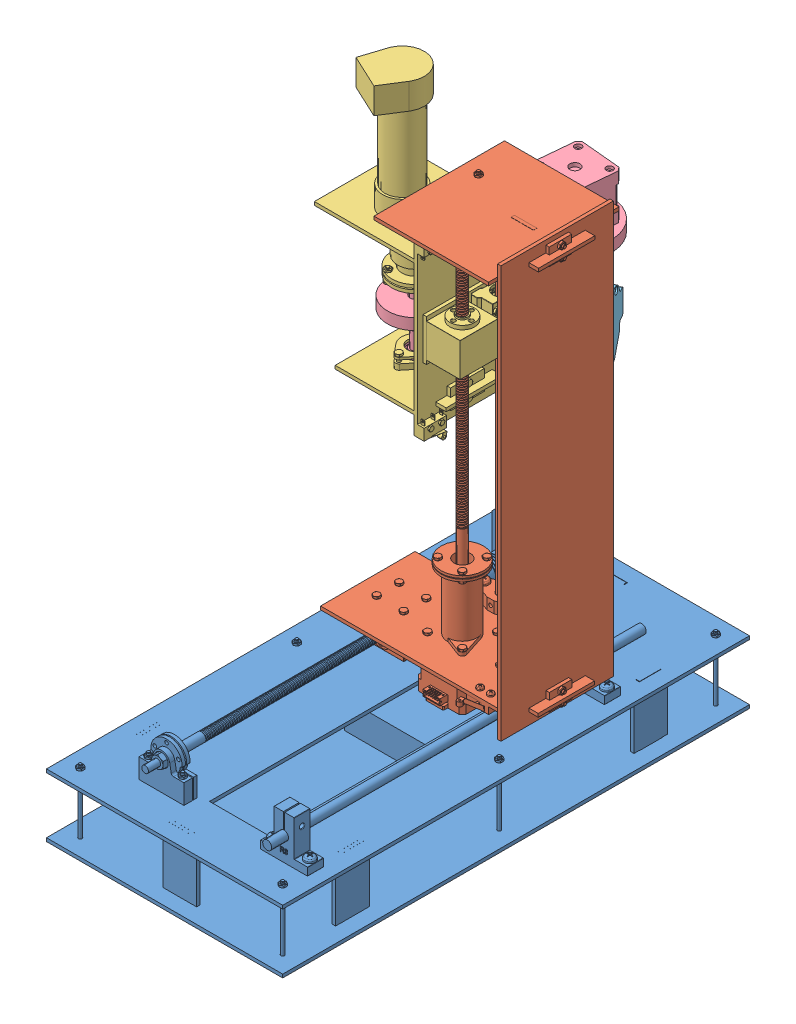
SolidWorks assembly Assembly, configuration Default. Lengths in mm.
Overall size (219.28 499.11 440.16).
7 component instances, 7 part files, 21 mates.
Components (placement in the parent):
- base link-1: base link [Default] x (0 0 1) z (0 1 0) size (415.01 210.01 110.32)
- Prismatic_1-1: Prismatic_1 [Default] at (210.765 96.0075 126.7261) x (-1 -0.000229 0) z (-0.000229 1 0) size (179.91 125.08 396.05)
- Prismatic_2-1: Prismatic_2 [Default] at (32.4506 267.8068 107.7472) x (1 0.000229 0) z (-0.000229 1 0) size (125.03 83.01 254.35)
- revoluteArm-1: revoluteArm [Default] at (55.6418 309.3227 -3.0616) x (0.995609 0.000228 0.093608) z (-0.000229 1 0) size (70.73 187.51 128.65)
- EndEffector base part-1: EndEffector base part [Default] at (72.7964 200.3266 -24.7835) x (0.87746 0.000201 -0.47965) z (-0.000229 1 0) size (58.3 83.63 102.5)
- Mirrorgrip arm-4: Mirrorgrip arm [Default] at (58.0879 196.5732 5.224) x (-0.000229 1 0) z (-0.47965 -0.00011 -0.87746) size (50 25 15)
- grip arm-3: grip arm [Default] at (82.7899 196.5789 50.4132) x (-0.000229 1 0) z (-0.47965 -0.00011 -0.87746) size (50 25 15)
Mates (geometry in assembly coordinates):
- Coincident49: coincident anti-aligned: plane of base link-1 through (105 0 207.5) normal (0 -1 0)
- Coincident51: coincident anti-aligned: plane of base link-1 through (210 53 0) normal (0 0 -1)
- Coincident50: coincident anti-aligned: plane of base link-1 through (0 3 415) normal (-1 0 0)
- Concentric1: concentric anti-aligned: cylinder of base link-1 through (69.2685 81 146.5661) axis (0 0 -1) radius 4; cylinder of Prismatic_1-1 through (69.2685 81 183.7261) axis (0 0 1) radius 5.25
- Concentric2: concentric aligned: cylinder of base link-1 through (177.7694 77 63.5661) axis (0 0 1) radius 4; cylinder of Prismatic_1-1 through (177.7694 77 153.2261) axis (0 0 1) radius 4
- Concentric3: concentric aligned: cylinder of Prismatic_1-1 through (123.3997 381.9876 168.7261) axis (-0.000229 1 0) radius 4; cylinder of Prismatic_2-1 through (123.4092 340.2776 168.7261) axis (-0.000229 1 0) radius 5.25
- Concentric4: concentric anti-aligned: cylinder of Prismatic_1-1 through (119.413 431.9867 129.7261) axis (0.000229 -1 0) radius 4; cylinder of Prismatic_2-1 through (119.4405 311.7767 129.7261) axis (-0.000229 1 0) radius 4
- Concentric5: concentric anti-aligned: cylinder of Prismatic_2-1 through (62.4383 336.1636 149.2439) axis (0.000229 -1 0) radius 5; cylinder of revoluteArm-1 through (62.4549 263.1637 149.2439) axis (-0.000229 1 0) radius 4
- Coincident14: coincident anti-aligned: plane of Prismatic_2-1 through (62.4527 272.8137 149.2439) normal (-0.000229 1 0); plane of revoluteArm-1 through (54.2059 272.8118 147.4461) normal (0.000229 -1 0)
- Concentric6: concentric anti-aligned: cylinder of revoluteArm-1 through (74.582 317.327 19.812) axis (0.000229 -1 0) radius 2.5; cylinder of EndEffector base part-1 through (74.591 277.826 19.812) axis (-0.000229 1 0) radius 3.175
- Coincident5: coincident anti-aligned: plane of revoluteArm-1 through (74.5931 268.827 19.812) normal (-0.000229 1 0); plane of EndEffector base part-1 through (78.79 268.8279 27.4897) normal (0.000229 -1 0)
- Coincident43: coincident anti-aligned: plane of EndEffector base part-1 through (76.7944 235.3275 18.6128) normal (0.87746 0.000201 -0.47965); plane of Mirrorgrip arm-4 through (66.8625 196.5752 0.4275) normal (-0.87746 -0.000201 0.47965)
- Coincident42: coincident anti-aligned: plane of EndEffector base part-1 through (92.3885 211.5811 47.1303) normal (0.000229 -1 0); plane of Mirrorgrip arm-4 through (65.1042 211.5748 1.3868) normal (-0.000229 1 0)
- LimitDistance3: limit distance = 9.16 mm anti-aligned: plane of Prismatic_1-1 through (207.365 96.0068 126.7261) normal (0 0 -1); plane of base link-1 through (187.0694 63.3 117.5661) normal (0 0 1)
- LimitDistance4: limit distance = 9.16 mm anti-aligned: plane of Prismatic_2-1 through (105.4196 403.2235 180.7472) normal (-0.000229 1 0); plane of Prismatic_1-1 through (123.3928 412.3876 168.7262) normal (0.000229 -1 0)
- LimitAngle2: limit planar angle = 2.979801 rad anti-aligned: plane of Prismatic_2-1 through (102.4369 327.4978 149.2472) normal (-1 -0.000229 0); plane of revoluteArm-1 through (87.159 309.3299 153.0106) normal (0.988585 0.000226 0.150665)
- LimitAngle3: limit planar angle = 2.164798 rad aligned: plane of revoluteArm-1 through (62.7033 276.8243 28.9594) normal (-0.093608 -0.000021 0.995609); plane of EndEffector base part-1 through (102.7645 244.5599 30.0577) normal (0.87746 0.000201 -0.47965)
- LimitDistance8: limit distance = 11.775 mm aligned: plane of EndEffector base part-1 through (56.823 215.3229 -7.5063) normal (-0.47965 -0.00011 -0.87746); plane of Mirrorgrip arm-4 through (58.0879 196.5732 5.224) normal (-0.47965 -0.00011 -0.87746)
- Coincident47: coincident anti-aligned: plane of EndEffector base part-1 through (92.3885 211.5811 47.1303) normal (0.000229 -1 0); plane of grip arm-3 through (89.8062 211.5805 46.576) normal (-0.000229 1 0)
- Coincident48: coincident anti-aligned: plane of EndEffector base part-1 through (76.7944 235.3275 18.6128) normal (0.87746 0.000201 -0.47965); plane of grip arm-3 through (91.5645 196.5809 45.6167) normal (-0.87746 -0.000201 0.47965)
- LimitDistance9: limit distance = 1.725 mm aligned: plane of grip arm-3 through (82.7899 196.5789 50.4132) normal (0.47965 0.00011 0.87746); plane of EndEffector base part-1 through (88.0003 215.3301 49.5285) normal (0.47965 0.00011 0.87746)
